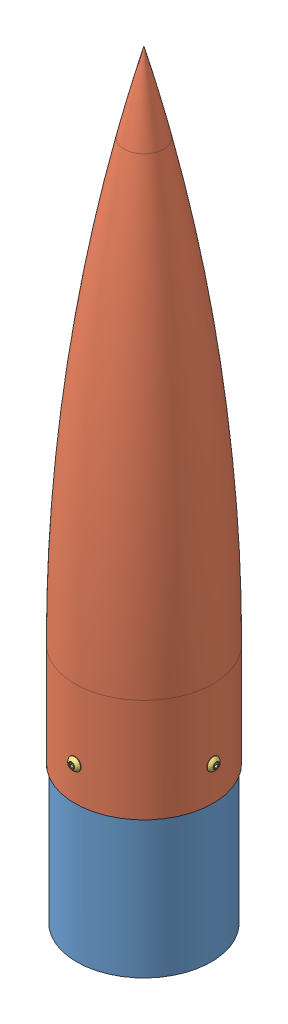
SolidWorks assembly nose_bay, configuration Default. Lengths in mm.
Overall size (106.73 558.8 106.73).
7 component instances, 3 part files, 4 mates.
Components (placement in the parent):
- nose_bay_internals-1: nose_bay_internals [Default] at (183.9499 -33.1295 -74.5602) size (99.06 152.4 99.06)
  - 6_in_coupler-1: 6_in_coupler [Default] at (-103.6757 17.4951 192.0836) size (99.06 152.4 99.06)
- nose_cone-1: nose_cone [Default] at (80.2742 85.9656 117.5235) size (101.6 457.2 101.6)
- 10_32_screw-1: 10_32_screw [90600A124] at (80.2742 111.3656 170.8889) size (9.17 9.17 15.64)
- 10_32_screw-2: 10_32_screw [90600A124] at (133.6396 111.3656 117.5235) x (0 0 -1) z (1 0 0) size (9.17 9.17 15.64)
- 10_32_screw-3: 10_32_screw [90600A124] at (80.2742 111.3656 64.1581) x (-1 0 0) z (0 0 -1) size (9.17 9.17 15.64)
- 10_32_screw-4: 10_32_screw [90600A124] at (26.9088 111.3656 117.5235) x (0 0 1) z (-1 0 0) size (9.17 9.17 15.64)
Mates (geometry in assembly coordinates):
- Concentric1: concentric aligned: cylinder of nose_bay_internals-1/6_in_coupler-1 through (80.2742 136.7656 117.5235) axis (0 -1 0) radius 49.53; cylinder of FG 4in 4.5-1 Ogive Nose Cone-1 through (80.2742 85.9656 117.5235) axis (0 -1 0) radius 49.53
- Distance1: distance = 101.6 mm aligned: plane of FG 4in 4.5-1 Ogive Nose Cone-1 through (80.2742 85.9656 117.5235) normal (0 -1 0); plane of nose_bay_internals-1/6_in_coupler-1 through (80.2742 -15.6344 117.5235) normal (0 -1 0)
- Concentric2: concentric anti-aligned: cylinder of FG 4in 4.5-1 Ogive Nose Cone-1 through (80.2742 111.3656 155.6235) axis (0 0 1) radius 1.9844; cylinder of 10_32_screw-1 through (80.2742 111.3656 155.6235) axis (0 0 -1) radius 4.5847
- Tangent1: tangent anti-aligned: cylinder of FG 4in 4.5-1 Ogive Nose Cone-1 through (80.2742 85.9656 117.5235) axis (0 -1 0) radius 50.8; plane of 10_32_screw-1 through (80.2742 115.9503 168.3235) normal (0 0 -1)
